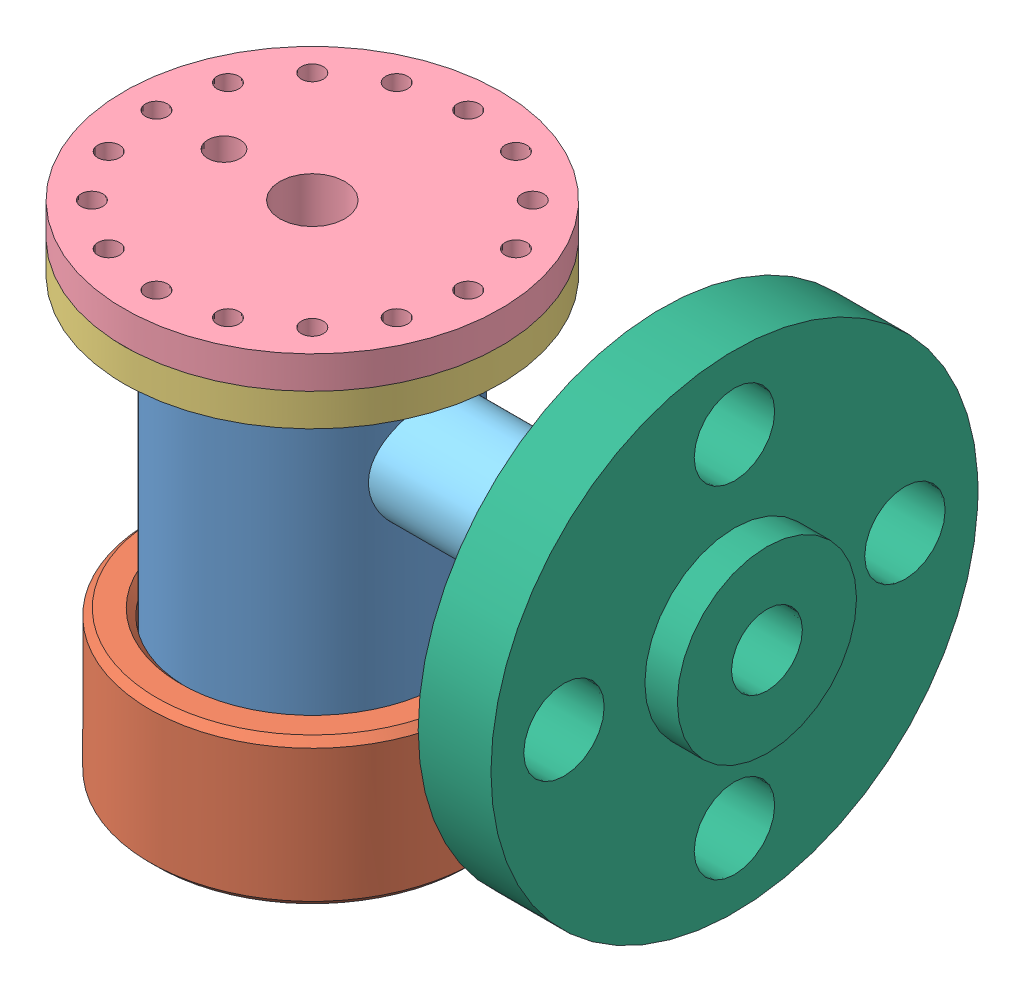
SolidWorks assembly [GG] Gas Generator, configuration Default. Lengths in mm.
Overall size (125.73 113.51 95.25).
6 component instances, 6 part files, 12 mates.
Components (placement in the parent):
- [GG] Chamber-1: [GG] Chamber [Default] at origin size (48.26 76.2 48.26)
- [GG] Chamber Bottom-1: [GG] Chamber Bottom [45515K228] at (0 -0.8001 0) x (0.999717 0 0.023781) z (0 -1 0) size (63.5 63.5 28.57)
- [GG] Chamber Flange-1: [GG] Chamber Flange [Default] at (0 69.85 0) size (73.66 6.35 73.66)
- [GG] Injector-1: [GG] Injector [Default] at (0 63.5 0) size (73.66 19.05 73.66)
- [GG] Outlet Pipe-1: [GG] Outlet Pipe [Default] at (69.85 50.8 0) x (0 0.988231 0.152967) z (-1 0 0) size (21.34 21.34 50.8)
- [GG] Outlet Pipe Flange-1: [GG] Outlet Pipe Flange [1503N21] at (88.9 50.8 0) x (0 0 -1) z (-1 0 0) size (95.25 95.25 28.7)
Mates (geometry in assembly coordinates):
- Concentric1: concentric anti-aligned: cylinder of [GG] Chamber-1 through (0 76.2 0) axis (0 -1 0) radius 24.13; cylinder of [GG] Chamber Bottom-1 through (0 13.4874 0) axis (0 1 0) radius 24.4094
- Coincident1: coincident anti-aligned: plane of [GG] Chamber-1 through (0 0 0) normal (0 -1 0); plane of [GG] Chamber Bottom-1 through (-0.5805 0 24.4025) normal (0 1 0)
- Coincident2: coincident aligned: circle of [GG] Chamber-1; circle of [GG] Chamber Flange-1
- Coincident3: coincident aligned: plane of [GG] Chamber Flange-1 through (0 69.85 0) normal (0 0 1)
- Concentric2: concentric aligned: cylinder of [GG] Chamber-1 through (0 76.2 0) axis (0 -1 0) radius 20.447; cylinder of [GG] Injector-1 through (0 63.5 0) axis (0 -1 0) radius 20.447
- Coincident4: coincident aligned: plane of [GG] Injector-1 through (0 63.5 0) normal (0 0 1)
- Coincident5: coincident anti-aligned: plane of [GG] Chamber Flange-1 through (0 76.2 0) normal (0 1 0); plane of [GG] Injector-1 through (-14.097 76.2 0) normal (0 -1 0)
- Concentric3: concentric anti-aligned: cylinder of [GG] Chamber-1 through (76.2 50.8 0) axis (-1 0 0) radius 10.668; cylinder of [GG] Outlet Pipe-1 through (19.05 50.8 0) axis (1 0 0) radius 10.668
- Distance1: distance = 19.05 mm: line of [GG] Chamber-1 through (76.2 0 76.2) axis (0 0 -1); plane of [GG] Outlet Pipe-1 through (19.05 50.8 0) normal (-1 0 0)
- Concentric5: concentric anti-aligned: cylinder of [GG] Outlet Pipe-1 through (19.05 50.8 0) axis (1 0 0) radius 10.668; cylinder of [GG] Outlet Pipe Flange-1 through (69.85 50.8 0) axis (-1 0 0) radius 11.176
- Coincident7: coincident anti-aligned: plane of [GG] Outlet Pipe-1 through (69.85 50.8 0) normal (1 0 0); plane of [GG] Outlet Pipe Flange-1 through (69.85 50.8 0) normal (-1 0 0)
- Coincident8: coincident anti-aligned: plane of [GG] Outlet Pipe Flange-1 through (88.9 50.8 0) normal (0 0 -1)
